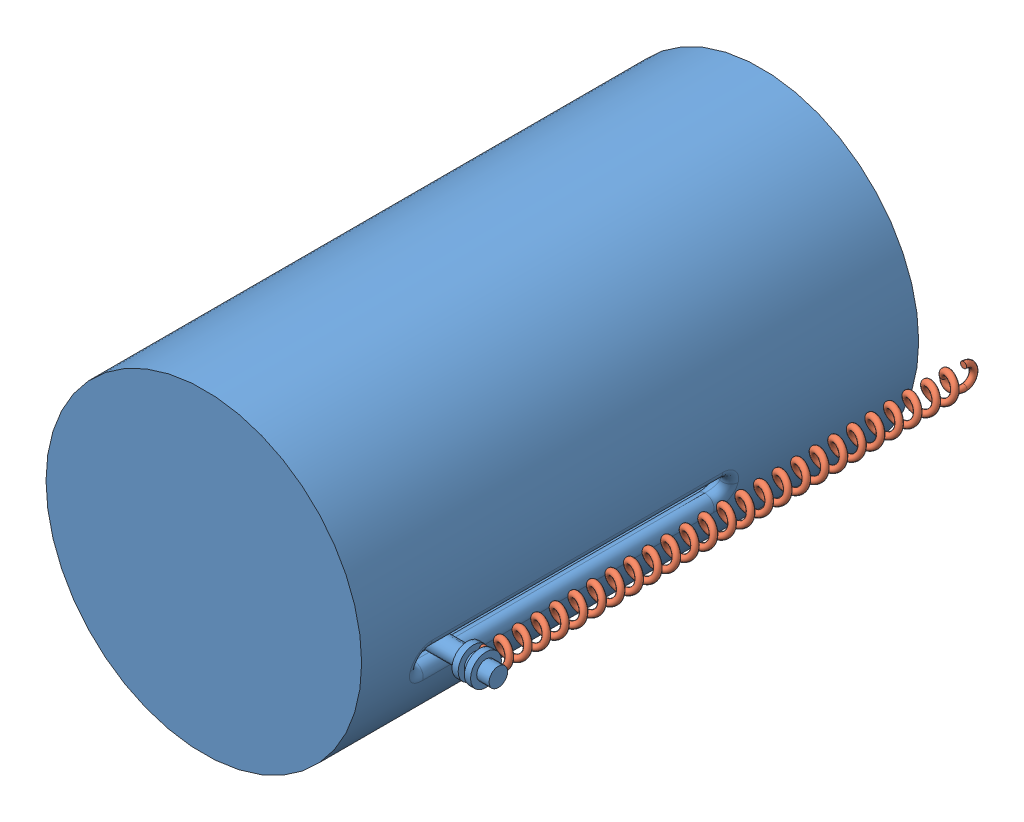
SolidWorks assembly spring assembly to the cylinder_11.06pm, configuration Default. Lengths in mm.
Overall size (66 51 94.92).
3 component instances, 2 part files, 5 mates.
Components (placement in the parent):
- bottom part-1: bottom part [Default] at (16.4612 51.9827 29.7161) size (66 51 90)
- spring-1: spring [Default] at (46.4612 46.5132 103.532) x (0 0.999821 0.018905) z (-1 0 0) size (5.47 82.4 5.47)
- spring-3: spring [Default] at (-13.5388 46.4913 103.5318) x (0 -0.999986 -0.005211) z (1 0 0) size (5.47 82.4 5.47)
Mates (geometry in assembly coordinates):
- Concentric1: concentric: cylinder of bottom part-1 through (-16.5388 46.483 105.1317) axis (1 0 0) radius 1.5; circle of spring-1
- Concentric2: concentric: circle of bottom part-1; circle of spring-1
- Coincident1: coincident: plane of bottom part-1 through (46.4612 46.483 105.1317) normal (-1 0 0); circle of spring-1
- Concentric4: concentric: cylinder of bottom part-1 through (-16.5388 46.483 105.1317) axis (1 0 0) radius 1.5; circle of spring-3
- Coincident2: coincident: plane of bottom part-1 through (-13.5388 46.483 105.1317) normal (1 0 0); circle of spring-3
